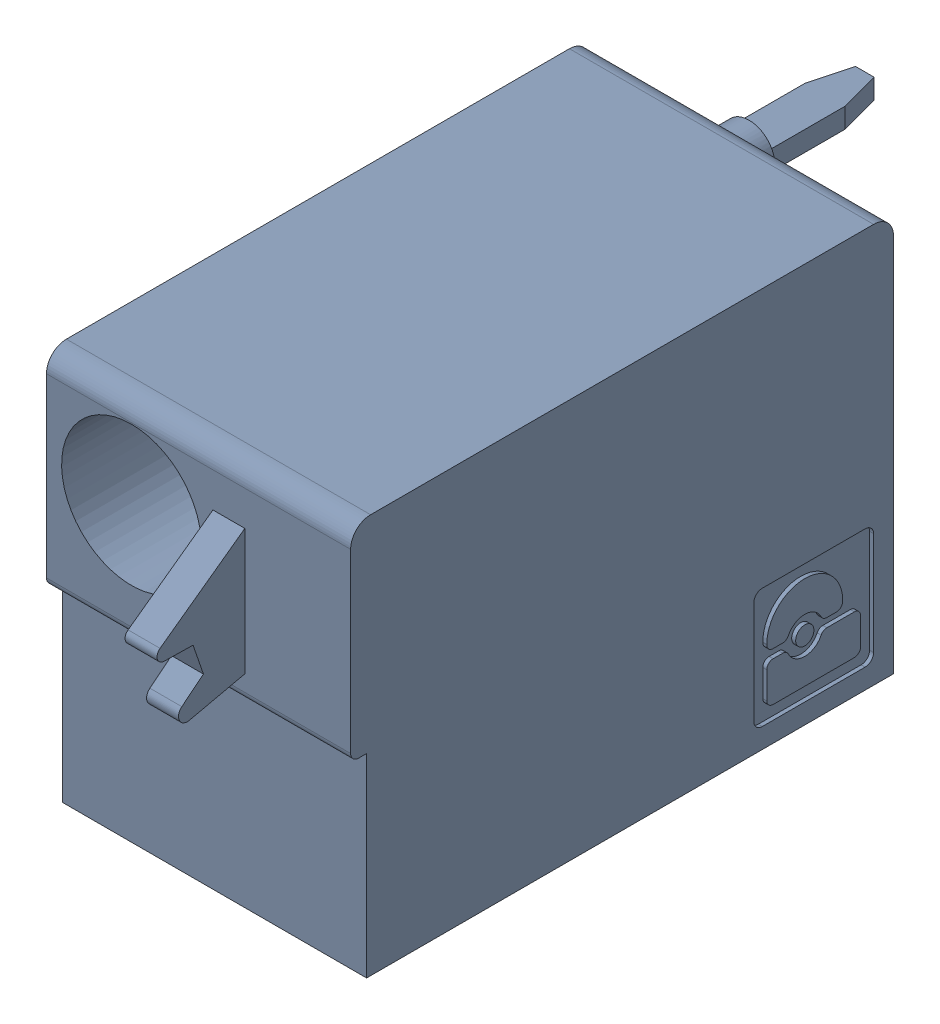
SolidWorks assembly J70, configuration Default. Lengths in mm.
Overall size (7.62 10 19.2).
2 component instances, 1 part files, 0 mates.
Components (placement in the parent):
- 1790487-1: 1790487 [Default] at (188.365 -15.67 -10.6) x (0 1 0) z (1 0 0) size (10 19.2 7.62)
  - ffkdsa1-v2-7.62-1: ffkdsa1-v2-7.62 [Default] at (-15.6914 -27.508 9.12) x (0 -1 0) z (0 0 1) size (19.2 10 7.62)
